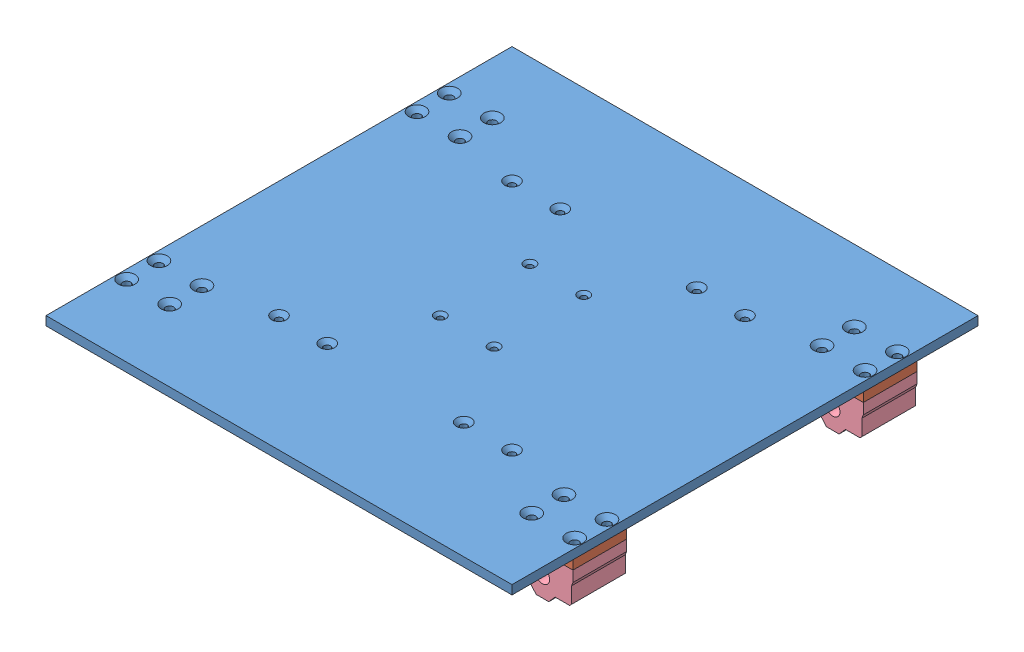
SolidWorks assembly Heated Bed, configuration Default. Lengths in mm.
Overall size (260 32 260).
17 component instances, 5 part files, 47 mates.
Components (placement in the parent):
- Plate-1: Plate [Default] at (78.4536 31.8193 65) x (1 0 0) z (0 1 0) size (260 260 5)
- Heat barrier-8: Heat barrier [Default] at (-147.5464 26.8193 1) x (-1 0 0) z (0 0 -1) size (34 5 30)
- RES-50_30W-8: RES-50_30W [Default] at (-103.093 31.8193 0) x (-0.743294 0 -0.668965) z (-0.668965 0 0.743294) size (27 14 43.24)
- SC8UU-8: SC8UU [Default] at (-164.5464 15.7232 31) x (-1 0 0) z (0 0 -1) size (34 22 30)
- Heat barrier-10: Heat barrier [Default] at (-147.5464 26.8193 -161) x (-1 0 0) z (0 0 -1) size (34 5 30)
- SC8UU-10: SC8UU [Default] at (-164.5464 15.7232 -131) x (-1 0 0) z (0 0 -1) size (34 22 30)
- RES-50_30W-10: RES-50_30W [Default] at (-103.0928 31.8193 -130) x (0.743294 0 0.668965) z (0.668965 0 -0.743294) size (27 14 43.24)
- Heat barrier-11: Heat barrier [Default] at (78.4536 26.8193 -161) x (-1 0 0) z (0 0 -1) size (34 5 30)
- SC8UU-11: SC8UU [Default] at (61.4536 15.7232 -131) x (-1 0 0) z (0 0 -1) size (34 22 30)
- RES-50_30W-11: RES-50_30W [Default] at (0.0002 31.8193 -130) x (-0.743294 0 -0.668965) z (-0.668965 0 0.743294) size (27 14 43.24)
- Heat barrier-12: Heat barrier [Default] at (78.4536 26.8193 1) x (-1 0 0) z (0 0 -1) size (34 5 30)
- SC8UU-12: SC8UU [Default] at (61.4536 15.7232 31) x (-1 0 0) z (0 0 -1) size (34 22 30)
- RES-50_30W-12: RES-50_30W [Default] at (0.0002 31.8193 0) x (-0.743294 0 -0.668965) z (-0.668965 0 0.743294) size (27 14 43.24)
- Belt Heat-barrier-3: Belt Heat-barrier [Default] at (-71.5464 26.8193 -90) size (40 5 10)
- Belt Heat-barrier-4: Belt Heat-barrier [Default] at (-71.5464 15.8193 -90) size (40 5 10)
- Belt Heat-barrier-5: Belt Heat-barrier [Default] at (-71.5464 26.8193 -40) size (40 5 10)
- Belt Heat-barrier-6: Belt Heat-barrier [Default] at (-71.5464 15.8193 -40) size (40 5 10)
Mates (geometry in assembly coordinates):
- Concentric1: concentric aligned: cylinder of Heat barrier-8 through (-152.5464 31.8193 25) axis (0 -1 0) radius 2.25; cylinder of SC8UU-8 through (-152.5464 26.8193 25) axis (0 -1 0) radius 2
- Concentric2: concentric aligned: cylinder of Heat barrier-8 through (-176.5464 31.8193 7) axis (0 -1 0) radius 2.25; cylinder of SC8UU-8 through (-176.5464 26.8193 7) axis (0 -1 0) radius 2
- Coincident1: coincident anti-aligned: plane of Heat barrier-8 through (-147.5464 26.8193 1) normal (0 -1 0); plane of SC8UU-8 through (-164.5464 26.8193 1) normal (0 1 0)
- Concentric3: concentric anti-aligned: cylinder of Heat barrier-8 through (-152.5464 31.8193 7) axis (0 -1 0) radius 2.25; cylinder of Plate-1 through (-152.5464 36.8193 7) axis (0 1 0) radius 2.25
- Concentric5: concentric anti-aligned: cylinder of Plate-1 through (-176.5464 36.8193 7) axis (0 1 0) radius 2.25; cylinder of Heat barrier-8 through (-176.5464 31.8193 7) axis (0 -1 0) radius 2.25
- Coincident2: coincident anti-aligned: plane of Plate-1 through (78.4536 31.8193 65) normal (0 -1 0); plane of Heat barrier-8 through (-147.5464 31.8193 1) normal (0 1 0)
- Coincident3: coincident anti-aligned: plane of Plate-1 through (78.4536 31.8193 65) normal (0 -1 0); plane of RES-50_30W-8 through (-107.1811 31.8193 15.1558) normal (0 1 0)
- Concentric11: concentric aligned: cylinder of Heat barrier-10 through (-152.5464 31.8193 -137) axis (0 -1 0) radius 2.25; cylinder of SC8UU-10 through (-152.5464 26.8193 -137) axis (0 -1 0) radius 2
- Concentric12: concentric aligned: cylinder of Heat barrier-10 through (-176.5464 31.8193 -155) axis (0 -1 0) radius 2.25; cylinder of SC8UU-10 through (-176.5464 26.8193 -155) axis (0 -1 0) radius 2
- Coincident5: coincident anti-aligned: plane of Heat barrier-10 through (-147.5464 26.8193 -161) normal (0 -1 0); plane of SC8UU-10 through (-164.5464 26.8193 -161) normal (0 1 0)
- Concentric13: concentric anti-aligned: cylinder of Plate-1 through (-152.5464 36.8193 -155) axis (0 1 0) radius 2.25; cylinder of Heat barrier-10 through (-152.5464 31.8193 -155) axis (0 -1 0) radius 2.25
- Concentric14: concentric anti-aligned: cylinder of Plate-1 through (-176.5464 36.8193 -155) axis (0 1 0) radius 2.25; cylinder of Heat barrier-10 through (-176.5464 31.8193 -155) axis (0 -1 0) radius 2.25
- Coincident6: coincident anti-aligned: plane of Plate-1 through (78.4536 31.8193 65) normal (0 -1 0); plane of Heat barrier-10 through (-147.5464 31.8193 -161) normal (0 1 0)
- Concentric15: concentric anti-aligned: cylinder of Plate-1 through (-89.6394 36.8193 -130) axis (0 1 0) radius 1.95; cylinder of RES-50_30W-10 through (-89.6391 31.8193 -130) axis (0 -1 0) radius 1.75
- Concentric16: concentric anti-aligned: cylinder of Plate-1 through (-116.5464 36.8193 -130) axis (0 1 0) radius 1.95; cylinder of RES-50_30W-10 through (-116.5464 31.8193 -130) axis (0 -1 0) radius 1.75
- Coincident7: coincident anti-aligned: plane of Plate-1 through (78.4536 31.8193 65) normal (0 -1 0); plane of RES-50_30W-10 through (-99.0046 31.8193 -145.1558) normal (0 1 0)
- Concentric17: concentric aligned: cylinder of Heat barrier-11 through (73.4536 31.8193 -137) axis (0 -1 0) radius 2.25; cylinder of SC8UU-11 through (73.4536 26.8193 -137) axis (0 -1 0) radius 2
- Concentric18: concentric aligned: cylinder of Heat barrier-11 through (49.4536 31.8193 -155) axis (0 -1 0) radius 2.25; cylinder of SC8UU-11 through (49.4536 26.8193 -155) axis (0 -1 0) radius 2
- Coincident8: coincident anti-aligned: plane of Heat barrier-11 through (78.4536 26.8193 -161) normal (0 -1 0); plane of SC8UU-11 through (61.4536 26.8193 -161) normal (0 1 0)
- Concentric19: concentric anti-aligned: cylinder of Plate-1 through (73.4536 36.8193 -155) axis (0 1 0) radius 2.25; cylinder of Heat barrier-11 through (73.4536 31.8193 -155) axis (0 -1 0) radius 2.25
- Concentric20: concentric anti-aligned: cylinder of Plate-1 through (49.4536 36.8193 -155) axis (0 1 0) radius 2.25; cylinder of Heat barrier-11 through (49.4536 31.8193 -155) axis (0 -1 0) radius 2.25
- Coincident9: coincident anti-aligned: plane of Plate-1 through (78.4536 31.8193 65) normal (0 -1 0); plane of Heat barrier-11 through (78.4536 31.8193 -161) normal (0 1 0)
- Concentric21: concentric anti-aligned: cylinder of Plate-1 through (-13.4534 36.8193 -130) axis (0 1 0) radius 1.95; cylinder of RES-50_30W-11 through (-13.4534 31.8193 -130) axis (0 -1 0) radius 1.75
- Concentric22: concentric anti-aligned: cylinder of Plate-1 through (13.4536 36.8193 -130) axis (0 1 0) radius 1.95; cylinder of RES-50_30W-11 through (13.4539 31.8193 -130) axis (0 -1 0) radius 1.75
- Coincident10: coincident anti-aligned: plane of Plate-1 through (78.4536 31.8193 65) normal (0 -1 0); plane of RES-50_30W-11 through (-4.0879 31.8193 -114.8442) normal (0 1 0)
- Concentric23: concentric aligned: cylinder of Heat barrier-12 through (73.4536 31.8193 25) axis (0 -1 0) radius 2.25; cylinder of SC8UU-12 through (73.4536 26.8193 25) axis (0 -1 0) radius 2
- Concentric24: concentric aligned: cylinder of Heat barrier-12 through (49.4536 31.8193 7) axis (0 -1 0) radius 2.25; cylinder of SC8UU-12 through (49.4536 26.8193 7) axis (0 -1 0) radius 2
- Coincident11: coincident anti-aligned: plane of Heat barrier-12 through (78.4536 26.8193 1) normal (0 -1 0); plane of SC8UU-12 through (61.4536 26.8193 1) normal (0 1 0)
- Concentric25: concentric anti-aligned: cylinder of Plate-1 through (73.4536 36.8193 7) axis (0 1 0) radius 2.25; cylinder of Heat barrier-12 through (73.4536 31.8193 7) axis (0 -1 0) radius 2.25
- Concentric26: concentric anti-aligned: cylinder of Plate-1 through (49.4536 36.8193 7) axis (0 1 0) radius 2.25; cylinder of Heat barrier-12 through (49.4536 31.8193 7) axis (0 -1 0) radius 2.25
- Coincident12: coincident anti-aligned: plane of Plate-1 through (78.4536 31.8193 65) normal (0 -1 0); plane of Heat barrier-12 through (78.4536 31.8193 1) normal (0 1 0)
- Concentric27: concentric anti-aligned: cylinder of Plate-1 through (-13.4534 36.8193 0) axis (0 1 0) radius 1.95; cylinder of RES-50_30W-12 through (-13.4534 31.8193 0) axis (0 -1 0) radius 1.75
- Concentric28: concentric anti-aligned: cylinder of Plate-1 through (13.4536 36.8193 0) axis (0 1 0) radius 1.95; cylinder of RES-50_30W-12 through (13.4539 31.8193 0) axis (0 -1 0) radius 1.75
- Coincident13: coincident anti-aligned: plane of Plate-1 through (78.4536 31.8193 65) normal (0 -1 0); plane of RES-50_30W-12 through (-4.0879 31.8193 15.1558) normal (0 1 0)
- Concentric29: concentric anti-aligned: cylinder of RES-50_30W-8 through (-89.6394 31.8193 0) axis (0 -1 0) radius 1.75; cylinder of Plate-1 through (-89.6394 36.8193 0) axis (0 1 0) radius 1.95
- Concentric31: concentric anti-aligned: cylinder of Plate-1 through (-41.5464 36.8193 -95) axis (0 1 0) radius 1.7; cylinder of Belt Heat-barrier-3 through (-41.5464 31.8193 -95) axis (0 -1 0) radius 1.75
- Concentric32: concentric aligned: cylinder of Plate-1 through (-71.5464 36.8193 -95) axis (0 1 0) radius 1.7; circle of Belt Heat-barrier-3
- Coincident14: coincident anti-aligned: plane of Plate-1 through (78.4536 31.8193 65) normal (0 -1 0); plane of Belt Heat-barrier-3 through (-71.5464 31.8193 -95) normal (0 1 0)
- Concentric33: concentric aligned: cylinder of Belt Heat-barrier-3 through (-41.5464 31.8193 -95) axis (0 -1 0) radius 1.75; cylinder of Belt Heat-barrier-4 through (-41.5464 20.8193 -95) axis (0 -1 0) radius 1.75
- Concentric34: concentric aligned: cylinder of Belt Heat-barrier-3 through (-71.5464 31.8193 -95) axis (0 -1 0) radius 1.75; cylinder of Belt Heat-barrier-4 through (-71.5464 20.8193 -95) axis (0 -1 0) radius 1.75
- Distance1: distance = 6 mm anti-aligned: plane of Belt Heat-barrier-3 through (-71.5464 26.8193 -95) normal (0 -1 0); plane of Belt Heat-barrier-4 through (-71.5464 20.8193 -95) normal (0 1 0)
- Concentric35: concentric aligned: cylinder of Belt Heat-barrier-5 through (-41.5464 31.8193 -45) axis (0 -1 0) radius 1.75; cylinder of Belt Heat-barrier-6 through (-41.5464 20.8193 -45) axis (0 -1 0) radius 1.75
- Concentric36: concentric aligned: cylinder of Belt Heat-barrier-5 through (-71.5464 31.8193 -45) axis (0 -1 0) radius 1.75; cylinder of Belt Heat-barrier-6 through (-71.5464 20.8193 -45) axis (0 -1 0) radius 1.75
- Distance2: distance = 6 mm anti-aligned: plane of Belt Heat-barrier-5 through (-71.5464 26.8193 -45) normal (0 -1 0); plane of Belt Heat-barrier-6 through (-71.5464 20.8193 -45) normal (0 1 0)
- Concentric37: concentric anti-aligned: cylinder of Plate-1 through (-41.5464 36.8193 -45) axis (0 1 0) radius 1.7; cylinder of Belt Heat-barrier-5 through (-41.5464 31.8193 -45) axis (0 -1 0) radius 1.75
- Concentric38: concentric aligned: cylinder of Plate-1 through (-71.5464 36.8193 -45) axis (0 1 0) radius 1.7; circle of Belt Heat-barrier-5
- Coincident16: coincident anti-aligned: plane of Plate-1 through (78.4536 31.8193 65) normal (0 -1 0); plane of Belt Heat-barrier-5 through (-71.5464 31.8193 -45) normal (0 1 0)
